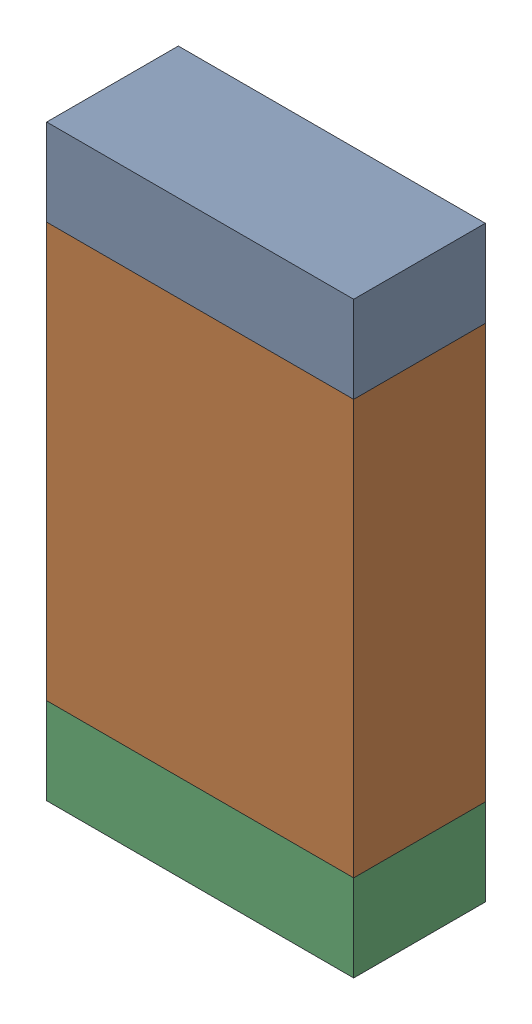
SolidWorks assembly R02-2, configuration Default. Lengths in mm.
Overall size (1.75 3.35 0.75).
6 component instances, 2 part files, 0 mates.
Components (placement in the parent):
- 959207032-2-1: 959207032-2 [Default] at (128.1431 81.3844 0) size (1.75 0.49 0.75)
  - Extruded-66-1: Extruded-66 [Default] at origin size (1.75 0.49 0.75)
- 959207168-2-1: 959207168-2 [Default] at (128.1431 79.9569 0) size (1.75 2.36 0.75)
  - Extruded-67-1: Extruded-67 [Default] at origin size (1.75 2.36 0.75)
- 959207032-2-2: 959207032-2 [Default] at (128.1431 78.5294 0) size (1.75 0.49 0.75)
  - Extruded-66-1: Extruded-66 [Default] at origin size (1.75 0.49 0.75)
